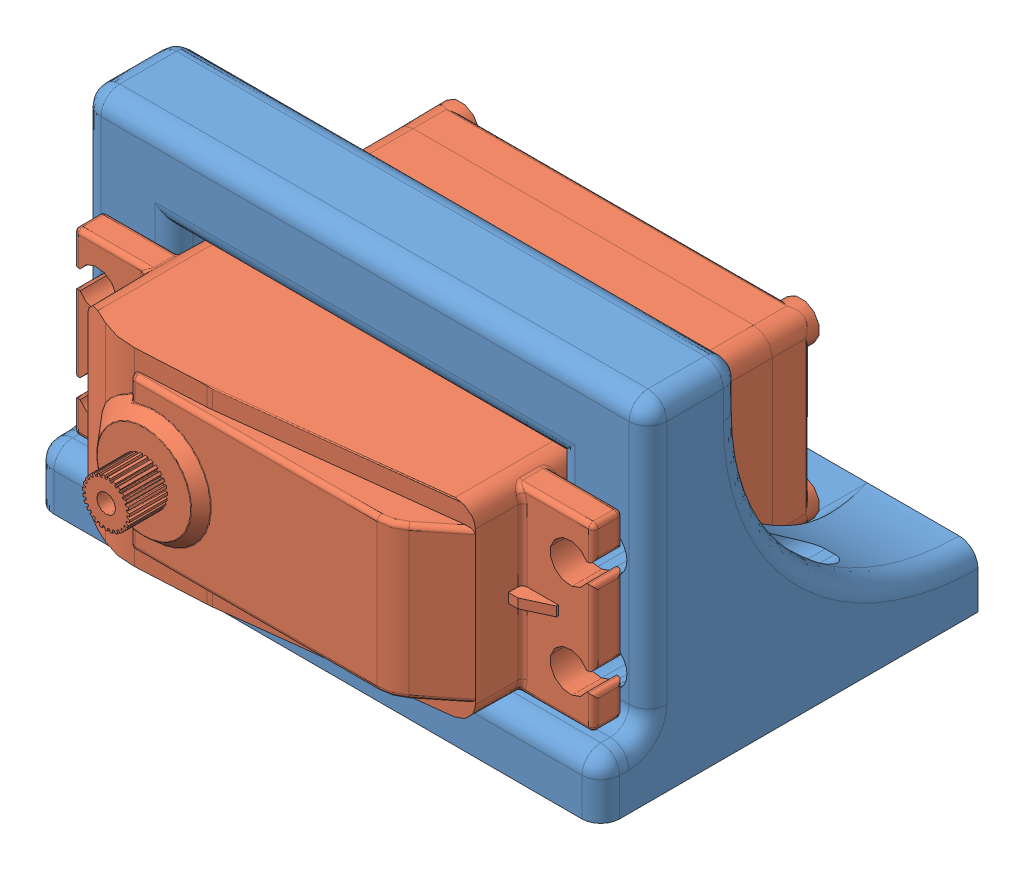
SolidWorks assembly Servo_Assembly_smaller, configuration Default. Lengths in mm.
Overall size (60 36 52.3).
2 component instances, 2 part files, 3 mates.
Components (placement in the parent):
- 20kg_Servo_Holder-1: 20kg_Servo_Holder [Smaller] at origin size (60 36 40)
- Servo 20kg-1: Servo 20kg [Default] at (29.8 15.05 -33.35) x (-1 0 0) z (0 1 0) size (55.1 45.65 20.12)
Mates (geometry in assembly coordinates):
- Coincident1: coincident anti-aligned: plane of 20kg_Servo_Holder-1 through (0 35 -5) normal (0 0 1); plane of Servo 20kg-1 through (54.85 20.05 -5) normal (0 0 -1)
- Coincident2: coincident anti-aligned: plane of 20kg_Servo_Holder-1 through (0 5 0) normal (0 1 0); plane of Servo 20kg-1 through (9.75 5 7.15) normal (0 -1 0)
- Coincident3: coincident anti-aligned: plane of 20kg_Servo_Holder-1 through (9.75 35 -5) normal (1 0 0); plane of Servo 20kg-1 through (9.75 25.1 7.15) normal (-1 0 0)
